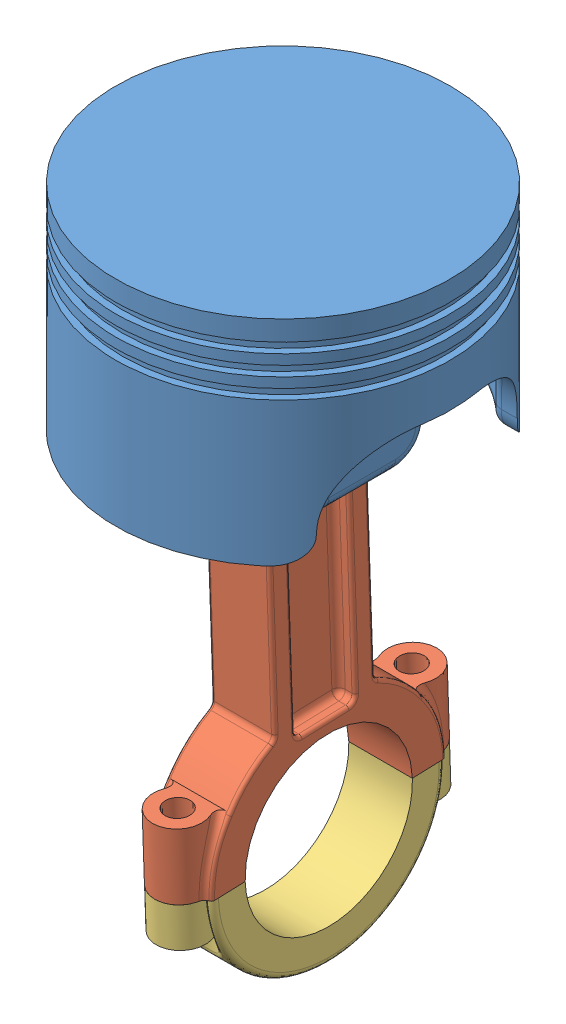
SolidWorks assembly Piston, configuration Default. Lengths in mm.
Overall size (127 255.71 127).
4 component instances, 4 part files, 7 mates.
Components (placement in the parent):
- Piston Head-1: Piston Head [Default] at (47.2609 110.7982 95.3364) size (127 82.5 127)
- Piston Rod-1: Piston Rod [Default] at (47.2659 -22.4557 92.6856) x (1 0 0) z (0 0.999395 0.034787) size (31.75 107.95 190.5)
- Piston Rod Cap-1: Piston Rod Cap [Default] at (47.2659 -98.6095 90.0349) x (-1 0 0) z (0 -0.034787 0.999395) size (26.54 45.22 107.95)
- Piston Pin-1: Piston Pin [Default] at (47.2159 53.6982 95.3364) x (0 0.952121 -0.305721) z (0 0.305721 0.952121) size (25.4 69.85 25.4)
Mates (geometry in assembly coordinates):
- Concentric1: concentric aligned: cylinder of Piston Head-1 through (109.8809 53.6982 95.3364) axis (-1 0 0) radius 12.7; cylinder of Piston Rod-1 through (59.3309 53.6982 95.3364) axis (-1 0 0) radius 25.4
- Coincident1: coincident anti-aligned: plane of Piston Head-1 through (63.1409 28.2982 74.7297) normal (-1 0 0); plane of Piston Rod-1 through (63.1409 53.6982 95.3364) normal (1 0 0)
- Coincident2: coincident anti-aligned: plane of Piston Rod-1 through (59.3309 -98.6095 90.0349) normal (0 -0.999395 -0.034787); plane of Piston Rod Cap-1 through (35.2009 -97.5051 58.3041) normal (0 0.999395 0.034787)
- Concentric2: concentric aligned: cylinder of Piston Rod-1 through (47.2659 -64.6829 46.7389) axis (0 -0.999395 -0.034787) radius 4.76; cylinder of Piston Rod Cap-1 through (47.2659 -112.304 45.0813) axis (0 -0.999395 -0.034787) radius 4.2164
- Concentric3: concentric aligned: cylinder of Piston Rod-1 through (47.2659 -67.7754 135.5851) axis (0 -0.999395 -0.034787) radius 4.76; cylinder of Piston Rod Cap-1 through (47.2659 -115.3966 133.9275) axis (0 -0.999395 -0.034787) radius 4.2164
- Concentric4: concentric anti-aligned: cylinder of Piston Head-1 through (109.8809 53.6982 95.3364) axis (-1 0 0) radius 12.7; cylinder of Piston Pin-1 through (12.2909 53.6982 95.3364) axis (1 0 0) radius 12.7
- Coincident3: coincident aligned: plane of Piston Head-1 through (82.1409 28.2982 74.7297) normal (1 0 0); plane of Piston Pin-1 through (82.1409 53.6982 95.3364) normal (1 0 0)
